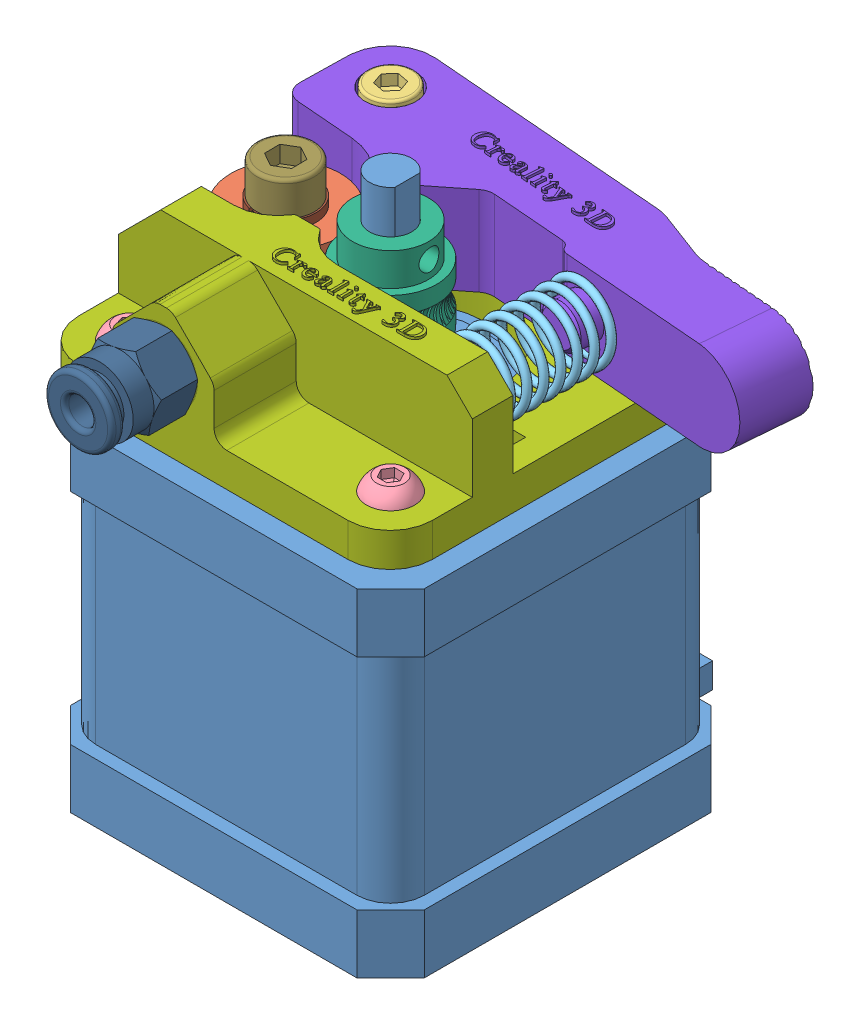
SolidWorks assembly ASM Extruder, configuration Standard. Lengths in mm.
Overall size (72.1 64 72.25).
13 component instances, 12 part files, 38 mates.
Components (placement in the parent):
- 40-42 motor-1: 40-42 motor [Standard] at origin size (42 64 50.7)
- 624U pillow-1: 624U pillow [Standard] at (17.9337 0.52 -131.5893) x (0 0 1) z (-1 0 0) size (13 4 13)
- M3X18 Socket Head Screw-1: M3X18 Socket Head Screw [Standard] at (60 56.0864 -71.9) x (0 -1 0) z (0.753538 0 0.657405) size (21 5.5 5.5)
- M3X10 Pan Head Screw-1: M3X10 Pan Head Screw [Standard] at (60 49.6964 -40.9) x (0 -1 0) z (-0.674609 0 0.738175) size (12.25 6.02 6.02)
- Extrusion Spring-1: Extrusion Spring [Standard] at (90.351 53.5739 -49.945) x (-0.996765 0.080374 0) z (0 0 -1) size (8.97 9.04 17.16)
- E gear-1: E gear [Standard] at (-2.8606 105.9729 -108.7529) x (0.998617 0 -0.052571) z (-0.052571 0 -0.998617) size (11.22 10.9 11.22)
- E housing 2-1: E housing 2 [Standard] at (118.2674 47.0731 -59.6786) x (-0.383049 0 0.923728) z (0 1 0) size (52.19 52.2 15.38)
- E idler tensioner-1: E idler tensioner [Standard] at (117.0877 47.0731 -54.9368) x (-0.456128 0 0.889914) z (0 1 0) size (42.36 54.28 10.86)
- M3X10 Flush Head Screw-1: M3X10 Flush Head Screw [Standard] at (91 48.5464 -71.9) x (0 -1 0) z (-0.538551 0 -0.842593) size (10 5.54 5.54)
- M6 Pneumatic joint-1: M6 Pneumatic joint [Standard] at (246.0139 147.0091 151.6385) x (0 0 1) z (-0.980697 -0.195531 0) size (15.42 8.01 9.24)
- M4 Split Washer-1: M4 Split Washer [Standard] at (62.3637 56.0464 -57.0893) x (-0.17437 0 0.98468) z (0.98468 0 0.17437) size (7.19 1 7.2)
- M4X8 Socket Head Screw-1: M4X8 Socket Head Screw [Standard] at (62.3637 56.0464 -57.0893) x (0 -1 0) z (-0.99993 0 0.011845) size (12 6.8 6.8)
- M3X10 Pan Head Screw-2: M3X10 Pan Head Screw [Standard] at (91 49.6964 -40.9) x (0 -1 0) z (-0.523408 0 0.852082) size (12.25 6.02 6.02)
Mates (geometry in assembly coordinates):
- Konzentrisch58: concentric: cylinder of 40-42 motor-1 through (75.5 65.5264 -56.4) axis (0 -1 0) radius 2.5; cylinder of E gear-1 through (75.5 49.0014 -56.4) axis (0 1 0) radius 2.5
- Deckungsgleich47: coincident: plane of 624U pillow-1 through (51.8739 51.0464 -44.2948) normal (0 -1 0); plane of E idler tensioner-1 through (58.9855 51.0464 -53.2948) normal (0 1 0)
- Konzentrisch55: concentric: cylinder of 624U pillow-1 through (58.9855 50.5464 -53.2948) axis (0 1 0) radius 2; cylinder of E idler tensioner-1 through (58.9855 48.0464 -53.2948) axis (0 1 0) radius 1.65
- Deckungsgleich48: coincident: plane of 624U pillow-1 through (66.9148 55.0464 -44.2948) normal (0 1 0); plane of M4 Split Washer-1 through (58.9855 55.0464 -53.2948) normal (0 -1 0)
- Konzentrisch56: concentric: cylinder of 624U pillow-1 through (58.9855 50.5464 -53.2948) axis (0 1 0) radius 2; cylinder of M4 Split Washer-1 through (58.9855 55.0464 -53.2948) axis (0 1 0) radius 2.1
- Konzentrisch57: concentric: cylinder of 624U pillow-1 through (58.9855 50.5464 -53.2948) axis (0 1 0) radius 2; cylinder of M4X8 Socket Head Screw-1 through (58.9855 56.988 -53.2948) axis (0 1 0) radius 2
- Deckungsgleich50: coincident: plane of 624U pillow-1; plane of E gear-1
- Konzentrisch54: concentric: cylinder of M3X18 Socket Head Screw-1 through (56.6218 40.0864 -68.1055) axis (0 1 0) radius 1.6; cylinder of E idler tensioner-1 through (56.6218 47.5439 -68.1055) axis (0 1 0) radius 1.608
- Deckungsgleich46: coincident: plane of M3X18 Socket Head Screw-1 through (58.4297 56.0864 -70.1778) normal (0 -1 0); plane of E idler tensioner-1 through (57.0714 56.0864 -73.6752) normal (0 1 0)
- Konzentrisch80: concentric: cylinder of M3X18 Socket Head Screw-1 through (56.6218 40.0864 -68.1055) axis (0 1 0) radius 1.6; cylinder of E housing 2-1 through (56.6218 44.0264 -68.1055) axis (0 1 0) radius 1.7587
- Deckungsgleich52: coincident: plane of M3X10 Pan Head Screw-1 through (60 48.0464 -40.9) normal (0 -1 0); plane of E housing 2-1 through (48.4838 47.5464 -73.2775) normal (0 1 0)
- Konzentrisch60: concentric: cylinder of M3X10 Pan Head Screw-1 through (64 41.5464 -57.7) axis (0 1 0) radius 1.5; cylinder of E housing 2-1 through (64 47.5464 -57.7) axis (0 1 0) radius 1.7587
- Konzentrisch77: concentric: cylinder of M3X10 Pan Head Screw-1 through (60.2081 42.0464 -37.3137) axis (0 1 0) radius 1.5; cylinder of E housing 2-1 through (60.2081 48.0464 -37.3137) axis (0 1 0) radius 1.7587
- Deckungsgleich70: coincident: plane of M3X10 Pan Head Screw-1 through (60.2081 48.0464 -37.3137) normal (0 -1 0); plane of E housing 2-1 through (73.886 48.0464 -54.5278) normal (0 1 0)
- Konzentrisch59: concentric: line of Extrusion Spring-1 through (55.8386 53.0739 -88.051) axis (-1 0 0); cylinder of E housing 2-1 through (54.955 53.0739 -88.051) axis (-1 0 0) radius 2.5125
- Deckungsgleich51: coincident: plane of Extrusion Spring-1; plane of E housing 2-1 through (54.955 61.1139 -52.1725) normal (-1 0 0)
- Konzentrisch79: concentric: line of Extrusion Spring-1 through (89.4112 53.5739 -48.9315) axis (-0.115688 0 -0.993286); cylinder of E housing 2-1 through (89.309 53.5739 -49.8092) axis (-0.115688 0 -0.993286) radius 2.5125
- Deckungsgleich73: coincident: plane of Extrusion Spring-1 through (96.4132 47.981 -50.6366) normal (0.115688 0 0.993286); plane of E housing 2-1 through (53.6714 61.6139 -45.6585) normal (-0.115688 0 -0.993286)
- Konzentrisch48: concentric: cylinder of E housing 2-1 through (69.7684 53.0714 -36.8893) axis (0.115688 0 0.993286) radius 2.5; cylinder of M6 Pneumatic joint-1 through (71.3881 53.0714 -22.9833) axis (0.115688 0 0.993286) radius 1.6
- Deckungsgleich42: coincident: plane of E housing 2-1 through (69.5275 43.5264 -94.3825) normal (1 0 0); plane of M6 Pneumatic joint-1 through (69.447 53.0714 -35.3725) normal (0 0 -1)
- Konzentrisch53: concentric: cylinder of E housing 2-1 through (33 43.5264 -57.7) axis (0 1 0) radius 1.7587; cylinder of E idler tensioner-1 through (33 58.0989 -57.7) axis (0 1 0) radius 3.015
- Deckungsgleich45: coincident: plane of E housing 2-1 through (48.4838 47.5464 -73.2775) normal (0 1 0); plane of E idler tensioner-1 through (50.0062 48.0464 -78.3127) normal (0 -1 0)
- Deckungsgleich53: coincident: plane of E housing 2-1 through (48.4838 47.5464 -73.2775) normal (0 1 0); plane of M3X10 Pan Head Screw-2 through (91 48.0464 -40.9) normal (0 -1 0)
- Konzentrisch61: concentric: cylinder of E housing 2-1 through (64 43.5264 -88.7) axis (0 1 0) radius 1.7587; cylinder of M3X10 Pan Head Screw-2 through (64 41.5464 -88.7) axis (0 1 0) radius 1.5
- Konzentrisch62: concentric: cylinder of E housing 2-1 through (33 43.5264 -88.7) axis (0 1 0) radius 1.7587; cylinder of M3X10 Flush Head Screw-1 through (33 38.147 -88.7) axis (0 1 0) radius 1.5293
- Tangential1: tangent: circle of E housing 2-1; cone of M3X10 Flush Head Screw-1 through (33 47.5577 -88.7) axis (0 -1 0)
- Konzentrisch78: concentric: cylinder of E housing 2-1 through (91 44.0264 -40.9) axis (0 1 0) radius 1.7587; cylinder of M3X10 Pan Head Screw-2 through (91 42.0464 -40.9) axis (0 1 0) radius 1.5
- Deckungsgleich71: coincident: plane of E housing 2-1 through (73.886 48.0464 -54.5278) normal (0 1 0); plane of M3X10 Pan Head Screw-2 through (91 48.0464 -40.9) normal (0 -1 0)
- Deckungsgleich72: coincident: plane of E housing 2-1 through (97.2838 44.0264 -36.067) normal (0.115688 0 0.993286); plane of M6 Pneumatic joint-1 through (70.2312 53.0714 -32.9162) normal (-0.115688 0 -0.993286)
- Deckungsgleich74: coincident: plane of E housing 2-1 through (73.886 48.0464 -54.5278) normal (0 1 0); plane of E idler tensioner-1 through (46.6281 48.0464 -74.5182) normal (0 -1 0)
- Abstand1: distance = 0.5 mm: plane of M3X10 Flush Head Screw-1 through (91 48.5464 -71.9) normal (0 1 0); plane of E housing 2-1 through (75.5775 48.0464 -56.4162) normal (0 1 0)
- Deckungsgleich49: coincident: plane of M4 Split Washer-1 through (58.9855 56.0464 -53.2948) normal (0 1 0); plane of M4X8 Socket Head Screw-1 through (59.0258 56.0464 -49.8951) normal (0 -1 0)
- Abstand2: distance = 2.5 mm: plane of E housing 2-1 through (75.5775 44.0264 -56.4162) normal (0 -1 0); plane of 40-42 motor-1 through (75.5 41.5264 -56.4) normal (0 1 0)
- Deckungsgleich75: coincident: plane of 40-42 motor-1 through (0 0 0) normal (0 0 1); plane of assembly
- Deckungsgleich76: coincident: plane of 40-42 motor-1 through (0 0 0) normal (0 1 0); plane of assembly
- Deckungsgleich77: coincident: plane of 40-42 motor-1 through (0 0 0) normal (1 0 0); plane of assembly
- Konzentrisch81: concentric: cylinder of 40-42 motor-1 through (91 36.5264 -40.9) axis (0 1 0) radius 1.5; cylinder of M3X10 Pan Head Screw-2 through (91 42.0464 -40.9) axis (0 1 0) radius 1.5
- Konzentrisch82: concentric: cylinder of 40-42 motor-1 through (60 36.5264 -71.9) axis (0 1 0) radius 1.5; cylinder of M3X18 Socket Head Screw-1 through (60 40.0864 -71.9) axis (0 1 0) radius 1.6
